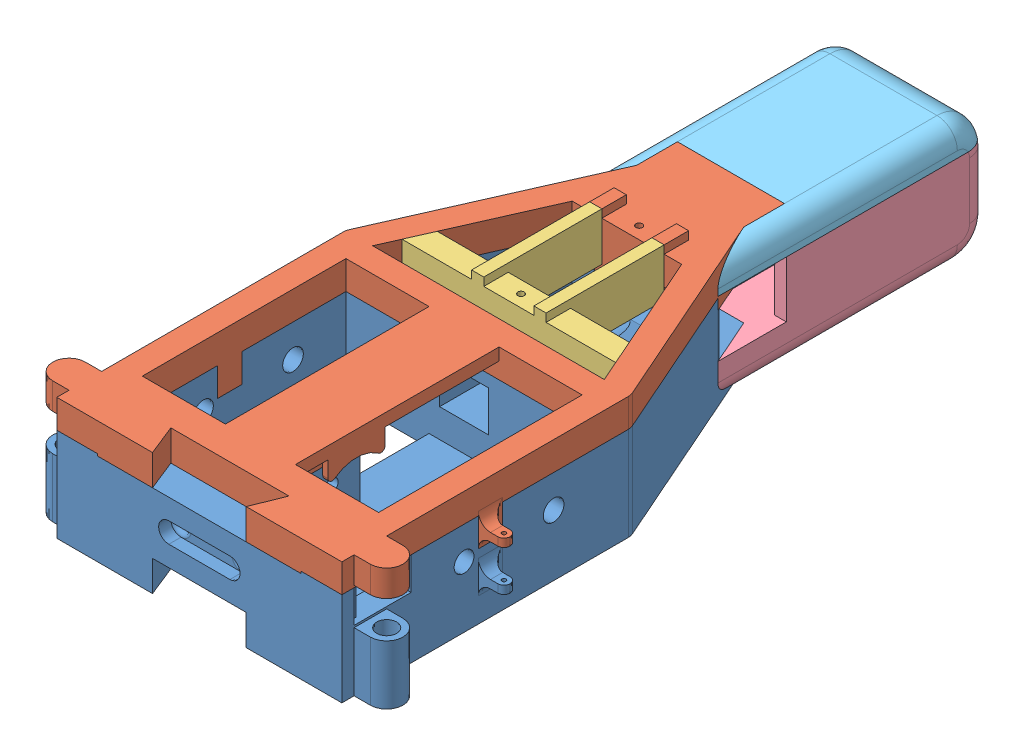
SolidWorks assembly front_body, configuration Default. Lengths in mm.
Overall size (86 32 176).
5 component instances, 5 part files, 15 mates.
Components (placement in the parent):
- body_bottom-1: body_bottom [Default] at (65.9565 51.0537 127.6703) size (86 23 130.54)
- body_top-1: body_top [Default] at (65.9565 51.0537 127.6703) size (86 16 130.54)
- servo_mount-1: servo_mount [Default] at (65.9565 51.0537 127.6703) size (57.15 11.8 31)
- battery_bottom-1: battery_bottom [Default] at (65.9565 51.0537 127.6703) size (36.88 23.4 66.79)
- battery_top-2: battery_top [Default] at (65.9565 51.0537 127.6703) size (36.85 9.6 66.79)
Mates (geometry in assembly coordinates):
- Coincident1: coincident anti-aligned: plane of body_bottom-1 through (85.7369 67.0537 126.6703) normal (0 0 -1); plane of body_top-1 through (107.2565 70.0537 126.6703) normal (0 0 1)
- Coincident3: coincident aligned: plane of body_bottom-1 through (100.9565 81.0537 89.1703) normal (1 0 0); plane of body_top-1 through (100.9565 81.0537 89.1703) normal (1 0 0)
- Coincident12: coincident anti-aligned: plane of body_top-1 through (52.5144 81.0537 55.1703) normal (0 0 1); plane of servo_mount-1 through (57.9565 74.0537 55.1703) normal (0 0 -1)
- Coincident17: coincident anti-aligned: plane of body_top-1 through (65.9565 77.0537 127.6703) normal (0 -1 0); plane of servo_mount-1 through (65.9565 77.0537 127.6703) normal (0 1 0)
- Coincident20: coincident anti-aligned: plane of body_top-1 through (73.1065 78.6537 53.1703) normal (1 0 0); plane of servo_mount-1 through (73.1065 78.6537 53.1703) normal (-1 0 0)
- Coincident21: coincident anti-aligned: plane of body_bottom-1 through (108.9565 74.0537 160.1703) normal (0 1 0); plane of body_top-1 through (65.9565 74.0537 127.6703) normal (0 -1 0)
- Coincident22: coincident anti-aligned: plane of battery_bottom-1 through (81.2565 500049.7513 -15.8297) normal (-1 0 0); plane of ? through (81.2565 73.1513 50.9594) normal (1 0 0)
- Coincident23: coincident anti-aligned: plane of battery_bottom-1 through (84.0987 73.1513 34.1703) normal (0 1 0); plane of ? through (65.9542 73.1513 127.6703) normal (0 -1 0)
- Coincident26: coincident aligned: plane of battery_bottom-1 through (65.9565 49.7513 -15.8297) normal (0 0 -1); plane of ? through (65.9542 49.7513 -15.8297) normal (0 0 -1)
- Coincident28: coincident anti-aligned: plane of body_bottom-1 through (65.9565 51.0537 29.6261) normal (0 0 -1); plane of battery_bottom-1 through (65.9565 51.0537 29.6261) normal (0 0 1)
- Coincident29: coincident anti-aligned: plane of body_bottom-1 through (79.0987 51.0537 29.6261) normal (1 0 0); plane of battery_bottom-1 through (79.0987 51.0537 29.6261) normal (-1 0 0)
- Coincident30: coincident aligned: plane of body_bottom-1 through (65.9565 51.0537 127.6703) normal (0 -1 0); plane of battery_bottom-1 through (65.9565 51.0537 127.6703) normal (0 -1 0)
- Coincident31: coincident anti-aligned: plane of body_top-1 through (65.9565 51.0537 29.6261) normal (0 0 -1); plane of battery_top-2 through (65.9565 51.0537 29.6261) normal (0 0 1)
- Coincident32: coincident anti-aligned: plane of body_top-1 through (79.0987 81.0537 29.6261) normal (1 0 0); plane of battery_top-2 through (79.0987 81.0537 29.6261) normal (-1 0 0)
- Coincident33: coincident anti-aligned: plane of body_top-1 through (79.0987 76.2537 29.6261) normal (0 -1 0); plane of battery_top-2 through (52.8142 76.2537 29.6261) normal (0 1 0)
